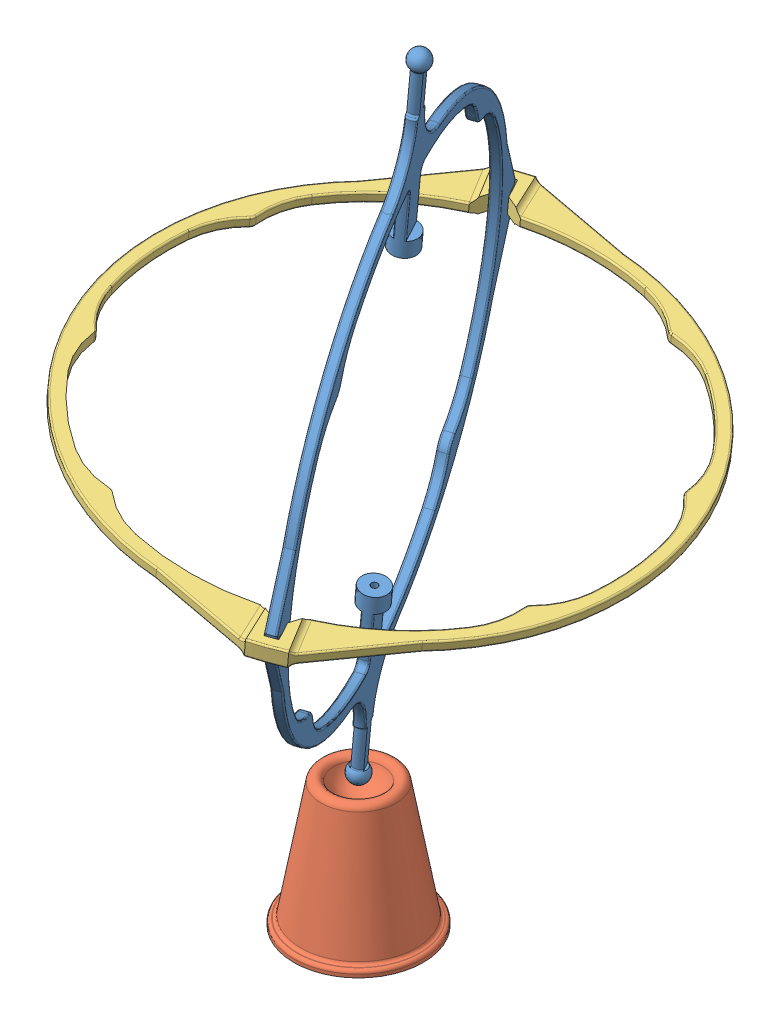
SolidWorks assembly Assem1, configuration Default. Lengths in mm.
Overall size (103.88 129.97 108.68).
3 component instances, 3 part files, 4 mates.
Components (placement in the parent):
- Main Frame-1: Main Frame [Default] at (55.7802 99.1063 146.3117) x (0.438823 -0.092621 0.893787) z (-0.128919 -0.990873 -0.039386) size (80.94 4 108)
- Spin Base-1: Spin Base [Default] at (49.012 47.0854 144.2439) size (20 20 20)
- Support Brace-1: Support Brace [Default] at (55.9046 99.0912 146.2827) x (0.438823 -0.092621 0.893787) z (-0.889277 0.097942 0.446758) size (84 2.53 75)
Mates (geometry in assembly coordinates):
- Coincident1: coincident anti-aligned: plane of Main Frame-1 through (55.21 99.9229 146.6763) normal (-0.128919 -0.990873 -0.039386); plane of Support Brace-1 through (56.0012 99.8344 146.3122) normal (0.128919 0.990873 0.039386)
- Coincident2: coincident anti-aligned: plane of Main Frame-1 through (55.1133 99.1797 146.6468) normal (-0.889277 0.097942 0.446758); plane of Support Brace-1 through (55.2876 100.4155 146.7228) normal (0.889277 -0.097942 -0.446758)
- Coincident3: coincident anti-aligned: plane of Main Frame-1 through (38.0123 102.7892 111.8159) normal (-0.438823 0.092621 -0.893787); plane of Support Brace-1 through (38.8871 103.4466 111.4545) normal (0.438823 -0.092621 0.893787)
- Concentric2: concentric: sphere of Main Frame-1; sphere of Spin Base-1
